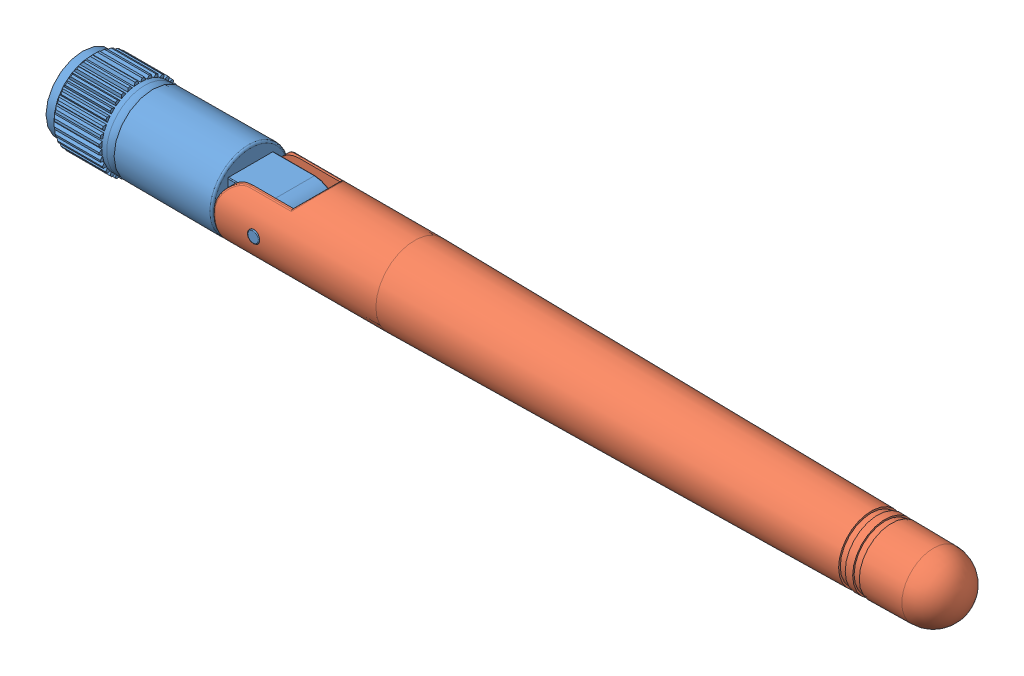
SolidWorks assembly Antenna assy, configuration 0. Lengths in mm.
Overall size (108.2 9.98 9.98).
2 component instances, 2 part files, 8 mates.
Components (placement in the parent):
- Antenna base-1: Antenna base [По умолчанию] at origin size (28.45 9.98 9.98)
- Antenna top-1: Antenna top [По умолчанию] at (20.7 0 0) size (87.5 9.5 9.5)
Mates (geometry in assembly coordinates):
- Совпадение1: coincident: plane of Antenna base-1 through (0 0 0) normal (0 0 1); plane of assembly through (0 0 0) normal (0 0 1)
- Совпадение2: coincident: plane of Antenna base-1 through (0 0 0) normal (0 1 0); plane of assembly through (0 0 0) normal (0 1 0)
- Совпадение3: coincident: plane of Antenna base-1 through (0 0 0) normal (1 0 0); plane of assembly through (0 0 0) normal (1 0 0)
- Совпадение4: coincident: plane of Antenna top-1 through (20.7 0 0) normal (0 0 1); plane of assembly through (0 0 0) normal (0 0 1)
- Концентричный1: concentric: cylinder of Antenna base-1 through (25.7 0 4.8) axis (0 0 -1) radius 0.75; cylinder of Antenna top-1 through (25.7 0 -4.75) axis (0 0 1) radius 0.75
- Параллельность1: parallel: plane of Antenna top-1 through (20.7 0 0) normal (0 1 0); plane of assembly through (0 0 0) normal (0 1 0)
- Угол1: planar angle = 0.785398 rad: plane of Antenna top-1; plane of assembly through (0 0 0) normal (0 1 0)
- Угол2: planar angle = 1.570796 rad: plane of Antenna top-1; plane of assembly through (0 0 0) normal (0 1 0)
